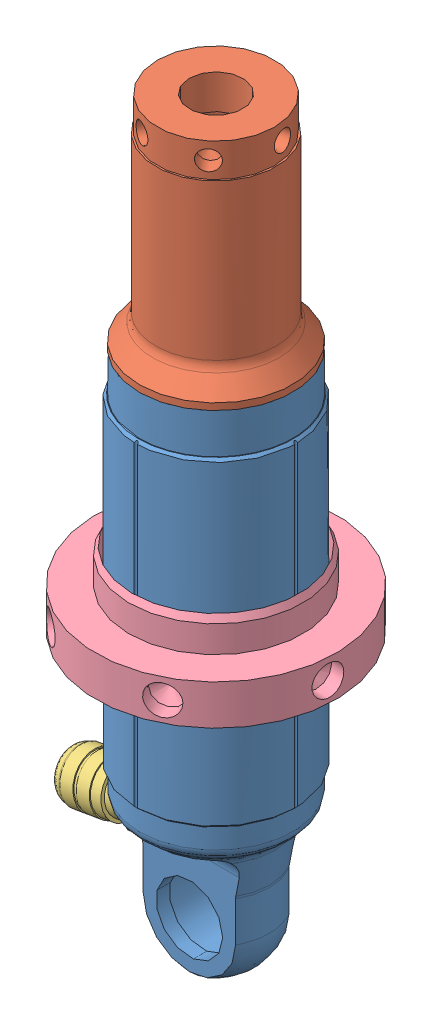
SolidWorks assembly Damper_Upper, configuration Default. Lengths in mm.
Overall size (77.49 179.39 77.49).
4 component instances, 4 part files, 5 mates.
Components (placement in the parent):
- Penske7800_LowerBody-1: Penske7800_LowerBody [Default] at (-36.6203 69.7482 -28.0619) size (38.18 127 38.18)
- Penske7800_UpperBody-1: Penske7800_UpperBody [Default] at (-36.6203 69.7482 -28.0619) x (0.755768 0 0.654839) z (-0.654839 0 0.755768) size (36.58 52.39 36.58)
- Penske7800_SchraederValve-1: Penske7800_SchraederValve [Default] at (-51.884 -31.1106 -28.0619) x (-0.139378 0.817473 -0.558849) z (-0.093928 0.550899 0.829269) size (12.7 22.23 12.7)
- Penske7800_SpringSeatAdjuster-1: Penske7800_SpringSeatAdjuster [Default] at (-36.6203 11.6042 -28.0619) x (-0.878992 0 -0.476836) z (0.476836 0 -0.878992) size (57.15 17.46 57.15)
Mates (geometry in assembly coordinates):
- Concentric1: concentric aligned: cylinder of Penske7800_LowerBody-1 through (-36.6203 -63.6028 -28.0619) axis (0 1 0) radius 16.6687; cylinder of Penske7800_UpperBody-1 through (-36.6203 122.1357 -28.0619) axis (0 1 0) radius 14.2875
- Coincident1: coincident anti-aligned: plane of Penske7800_LowerBody-1 through (-36.6203 69.7482 -28.0619) normal (0 1 0); plane of Penske7800_UpperBody-1 through (-48.596 69.7482 -14.2404) normal (0 -1 0)
- Concentric2: concentric aligned: cylinder of Penske7800_LowerBody-1 through (-50.0061 -30.7904 -28.0619) axis (-0.985774 -0.168074 0) radius 5.7544; cylinder of Penske7800_SchraederValve-1 through (-48.7542 -30.577 -28.0619) axis (-0.985774 -0.168074 0) radius 6.35
- Distance1: distance = 17.78 mm anti-aligned: plane of Penske7800_SchraederValve-1 through (-48.7542 -30.577 -28.0619) normal (0.985774 0.168074 0); plane of Penske7800_LowerBody-1 through (-47.5065 67.8921 -28.0619) normal (-0.985774 -0.168074 0)
- Concentric3: concentric aligned: cylinder of Penske7800_LowerBody-1 through (-36.6203 69.7482 -28.0619) axis (0 1 0) radius 18.2563; cylinder of Penske7800_SpringSeatAdjuster-1 through (-36.6203 90.5786 -28.0619) axis (0 1 0) radius 19.8438
